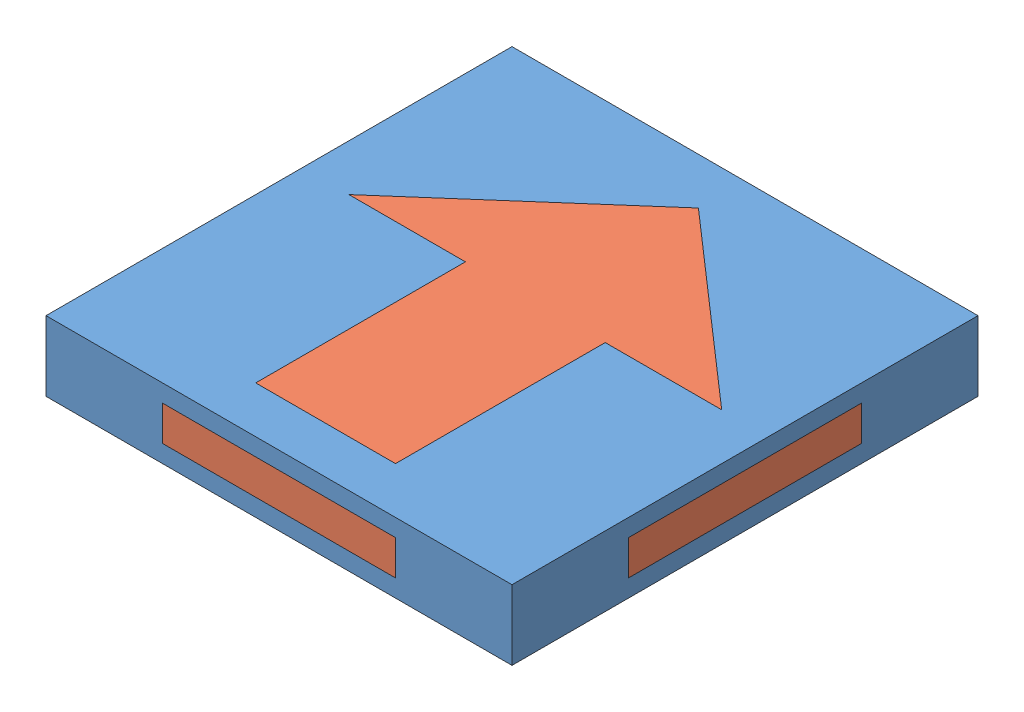
SolidWorks assembly Assem3, configuration Default. Lengths in mm.
Overall size (20 3 20).
2 component instances, 2 part files, 3 mates.
Components (placement in the parent):
- Arrow Outer-1: Arrow Outer [Default] at (6.0273 9.7205 16.5975) size (20 3 20)
- Arrow Inner-1: Arrow Inner [Default] at (6.0273 9.7205 16.5975) size (20 3 20)
Mates (geometry in assembly coordinates):
- Coincident1: coincident: plane of Arrow Outer-1 through (16.0273 12.7205 6.5975) normal (1 0 0); plane of Arrow Inner-1 through (16.0273 10.4705 18.9286) normal (1 0 0)
- Coincident2: coincident: plane of Arrow Outer-1 through (11.0273 11.9705 6.5975) normal (0 -1 0); plane of Arrow Inner-1 through (6.0273 11.9705 16.5975) normal (0 1 0)
- Coincident3: coincident anti-aligned: plane of Arrow Outer-1 through (-3.9727 10.4705 11.5975) normal (0 0 1); plane of Arrow Inner-1 through (6.0273 10.4705 11.5975) normal (0 0 -1)
